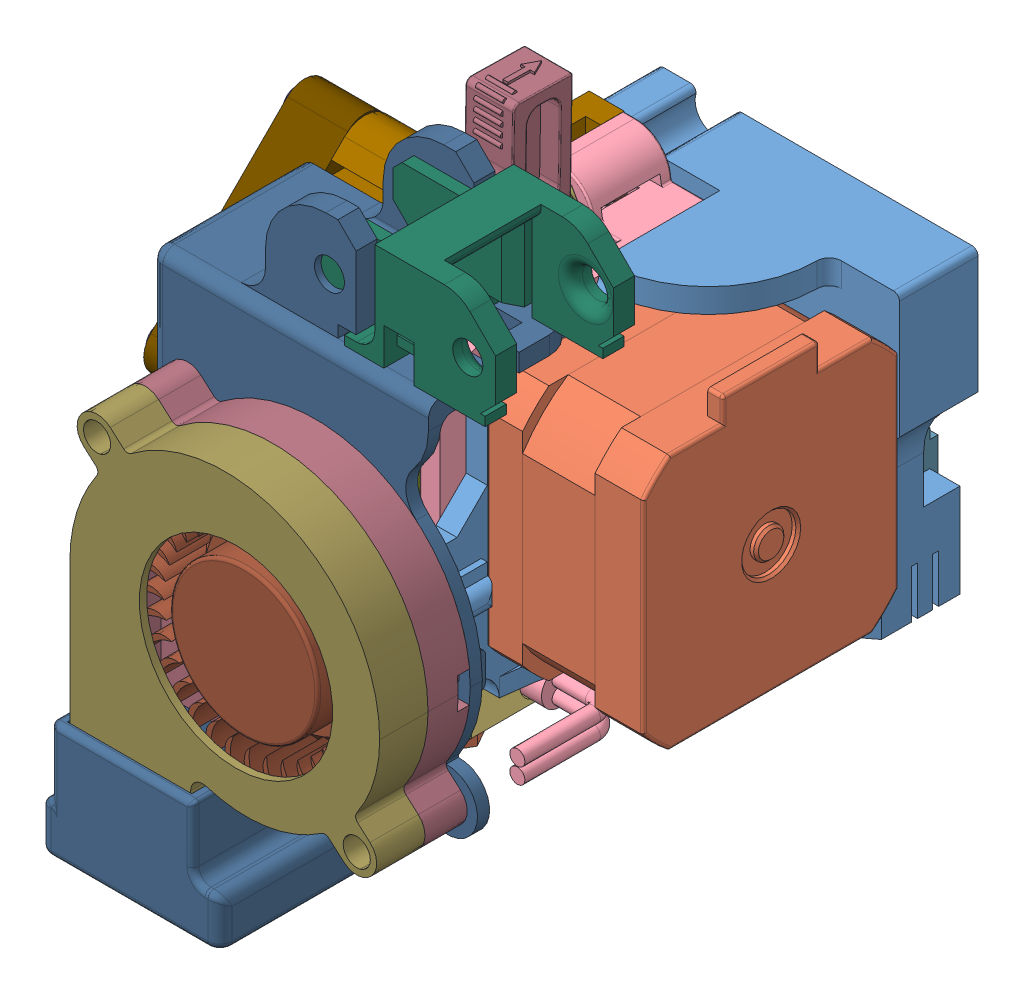
SolidWorks assembly Ensamblaje Titan Aero, configuration Predeterminado. Lengths in mm.
Overall size (76.87 98.82 99.88).
44 component instances, 33 part files, 26 mates.
Components (placement in the parent):
- X-CarriageV2 Titan-1: X-CarriageV2 Titan [Predeterminado] at origin size (55.25 51 75.5)
- Nema 17-1: Nema 17 [NEMA 17 L26] at (26.75 25.5 21) x (0 0 -1) z (1 0 0) size (42.3 46.3 50)
- LJ12A3-4-Z-1: LJ12A3-4-Z [По умолчанию] at (7.55 -17.2 54.5) x (-0.683398 0 0.730046) z (0 -1 0) size (12.21 12.27 81)
- e3d titan areo 1.751-1: e3d titan areo 1.751 [Predeterminado] at (23.25 25.5 21) x (0 0 -1) z (0 1 0) size (64.29 54.44 90.47)
  - Base-1: Base [Predeterminado] at origin size (46 23.41 49.98)
  - 9x5x3mm bearing-1: 9x5x3mm bearing [Predeterminado] at (-15.5 4 15.5) x (1 0 0) z (0 -1 0) size (9 9 3)
  - hobbed wheel-1: hobbed wheel [Predeterminado] at (-15.5 1.6 15.5) x (-0.447437 0 0.894315) z (0 1 0) size (8.6 8.58 20.6)
  - filament gear-1: filament gear [Predeterminado] at (-15.5 8.55 15.5) x (-0.894315 0 -0.447437) z (0 -1 0) size (34 34 4)
  - motor gear-1: motor gear [Predeterminado] at (0 8.5 0) x (-0.681998 0 -0.731354) z (0 -1 0) size (11.99 11.99 9)
  - cover-1: cover [Predeterminado] at (0 24.9 0) x (1 0 0) z (0 0 -1) size (52.63 28.17 55.14)
  - 9x5x3mm bearing-2: 9x5x3mm bearing [Predeterminado] at (-15.5 22.8 15.5) x (1 0 0) z (0 -1 0) size (9 9 3)
  - m3x8-1: m3x8 [Predeterminado] at (20.7 13.6 23.3) x (0 0 1) z (0 1 0) size (5.69 9.65 5.69)
  - M3 nut-1: M3 nut [Predeterminado] at (16.7 13.6 23.3) x (0 1 0) z (0 0 1) size (6.19 2.71 6.57)
  - idler spring-1: idler spring [Predeterminado] at (14.287 13.6 23.3) x (0 0 1) z (-1 0 0) size (6.43 6.45 12.02)
  - tensioner-1: tensioner [Predeterminado] at (0 13.6 0) x (0 -1 0) z (0.017452 0 0.999848) size (8.2 21.54 50.88)
  - idler bearing pin-1: idler bearing pin [Predeterminado] at (-5.2287 9.6 15.5936) x (0.999848 0 -0.017452) z (0 1 0) size (3.04 3.15 9)
  - idler bearing-1: idler bearing [Predeterminado] at (-5.2287 13.6 15.5936) x (0.999848 0 -0.017452) z (0 1 0) size (10 10 4)
  - guide tube-1: guide tube [Predeterminado] at (-10.9 13.6 -7.9) x (-1 0 0) z (0 0 1) size (10.9 16.1 22.25)
  - ISO 7380 - M3 x 28 v1-1: ISO 7380 - M3 x 28 v1 [Predeterminado] at (-15.5 25.94 15.5) x (0 -1 0) z (0 0 1) size (14.65 5.7 5.7)
  - ISO 7380 - M3 x 28 v1-2: ISO 7380 - M3 x 28 v1 [Predeterminado] at (15.5 25.94 15.5) x (0 -1 0) z (0 0 1) size (14.65 5.7 5.7)
  - ISO 7380 - M3 x 28 v1-3: ISO 7380 - M3 x 28 v1 [Predeterminado] at (15.5 25.94 -15.5) x (0 -1 0) z (0 0 1) size (14.65 5.7 5.7)
  - ISO 7380 - M3 x 28 v1-4: ISO 7380 - M3 x 28 v1 [Predeterminado] at (-21.7 25.94 -14.7) x (0 -1 0) z (0 0 -1) size (14.65 5.7 5.7)
  - Fan 40 X 40 X 10 v4-1: Fan 40 X 40 X 10 v4 [Predeterminado] at (-2.3 40.465 3.8274) x (0.707107 0 0.707107) z (-0.707107 0 0.707107) size (40 10.59 40)
  - E3D v6 HotEnd - Heatbreak-1: E3D v6 HotEnd - Heatbreak [Predeterminado] at (-10.9 13.6 -31.7812) x (0 1 0) z (0 0 -1) size (7 7 21.9)
  - E3D v6 HotEnd - Nozzle-1: E3D v6 HotEnd - Nozzle [Predeterminado] at (-10.4145 12.7757 -42.8188) x (0 1 0) z (0 0 -1) size (8.08 7 12.5)
  - E3D v6 HotEnd - Heat Block-1: E3D v6 HotEnd - Heat Block [Predeterminado] at (4.7289 21.3165 -38.3127) x (-1 0 0) z (0 1 0) size (20 11.5 16)
  - Ceramic Cartridge Heater-1: Ceramic Cartridge Heater [Predeterminado] at (-3.5983 1.9238 -34.2531) x (0 0 1) z (0 -1 0) size (6 18 29.25)
  - Thermistor-1: Thermistor [Predeterminado] at (-7 16.1 -36.0312) x (0 -0.5 0.866025) z (-1 0 0) size (1.5 1.5 7.6)
  - HEXAGON SOCKET HEAD CAP SCREWS_SCB3-4-1: HEXAGON SOCKET HEAD CAP SCREWS_SCB3-4 [Predeterminado] at (-2.4 14.6 -33.2312) x (0 1 0) z (1 0 0) size (5.5 5.5 7)
  - HEXAGON SOCKET HEAD CAP SCREWS_SCB3-10-1: HEXAGON SOCKET HEAD CAP SCREWS_SCB3-10 [Predeterminado] at (1.5308 13.8272 -37.4189) x (0 1 0) z (0 0 -1) size (5.5 5.5 13)
  - Flat Washers_PWF3-1: Flat Washers_PWF3 [Predeterminado] at (-2.4 14.6 -33.2312) x (0 1 0) z (1 0 0) size (6 6 0.5)
  - ISO 7380 - M3 x 28 v1-5: ISO 7380 - M3 x 28 v1 [Predeterminado] at (-2.3 45.465 26.4548) x (0 -1 0) z (0.707107 0 0.707107) size (14.65 5.7 5.7)
  - ISO 7380 - M3 x 28 v1-6: ISO 7380 - M3 x 28 v1 [Predeterminado] at (-24.9274 45.465 3.8274) x (0 -1 0) z (0.707107 0 0.707107) size (14.65 5.7 5.7)
  - ISO 7380 - M3 x 28 v1-7: ISO 7380 - M3 x 28 v1 [Predeterminado] at (-2.3 45.465 -18.8) x (0 -1 0) z (0.707107 0 0.707107) size (14.65 5.7 5.7)
  - ISO 7380 - M3 x 28 v1-8: ISO 7380 - M3 x 28 v1 [Predeterminado] at (20.3274 45.465 3.8274) x (0 -1 0) z (0.707107 0 0.707107) size (14.65 5.7 5.7)
- Гайка М12-1: Гайка М12 [По умолчанию] at (7.55 19.5 54.5) x (0.866025 0 0.5) z (0 -1 0) size (16.5 19.05 4.39)
- Гайка М12-2: Гайка М12 [По умолчанию] at (7.55 11.5 54.5) x (0.866025 0 0.5) z (0 -1 0) size (16.5 19.05 4.39)
- LayerFanSupport-Titan-1: LayerFanSupport-Titan [Predeterminado] at (-3.56 4.8 51.3) x (0 0 -1) z (0 -1 0) size (49.98 56.12 97.13)
- Radial-Cooling-Fan-5015-DC12V-1: Radial-Cooling-Fan-5015-DC12V [По умолчанию] at (24.44 25.4 66.3) x (1 0 0) z (0 -1 0) size (51.3 15 51.07)
  - turbine-1: turbine [По умолчанию] at (0 3.2 0) x (0.990476 0 -0.137682) z (0.137682 0 0.990476) size (38.96 10.5 38.91)
  - top-3: top [По умолчанию] at (0 15 0) size (51.3 8 51.07)
  - bottom-1: bottom [По умолчанию] at origin size (51.3 8.5 51.07)
- MGN12C-1: MGN12C [Predeterminado] at (42.3453 36.5334 -17) x (-0.999999 -0.001343 0) z (-0.001343 0.999999 0) size (34.7 10 27)
- Eslabon 15-2: Eslabon 15 [Predeterminado] at (50.915 79.5 45.7925) x (-1 0 0) z (0 0 1) size (34 17 23)
Mates (geometry in assembly coordinates):
- Concéntrica1: concentric aligned: cylinder of X-CarriageV2 Titan-1 through (58.1455 41 36.5) axis (-1 0 0) radius 1.55; cylinder of Nema 17-1 through (26.75 41 36.5) axis (-1 0 0) radius 1.25
- Concéntrica2: concentric aligned: cylinder of X-CarriageV2 Titan-1 through (58.1455 41 5.5) axis (-1 0 0) radius 1.55; circle of Nema 17-1
- Coincidente1: coincident anti-aligned: plane of X-CarriageV2 Titan-1 through (26.75 47 42) normal (1 0 0); plane of Nema 17-1 through (26.75 25.5 21) normal (-1 0 0)
- Concéntrica3: concentric anti-aligned: cylinder of X-CarriageV2 Titan-1 through (7.55 -1.8241 54.5) axis (0 1 0) radius 6.125; cylinder of LJ12A3-4-Z-1 through (7.55 -17.2 54.5) axis (0 -1 0) radius 5.25
- Concéntrica4: concentric anti-aligned: cylinder of X-CarriageV2 Titan-1 through (58.1455 41 5.5) axis (-1 0 0) radius 1.55; cylinder of e3d titan areo 1.751-1/Base-1 through (19.75 41 5.5) axis (1 0 0) radius 1.825
- Concéntrica5: concentric anti-aligned: cylinder of X-CarriageV2 Titan-1 through (58.1455 41 36.5) axis (-1 0 0) radius 1.55; cylinder of e3d titan areo 1.751-1/hobbed wheel-1 through (11.35 41 36.5) axis (1 0 0) radius 1.65
- Coincidente2: coincident anti-aligned: plane of X-CarriageV2 Titan-1 through (23.25 47 42) normal (-1 0 0); plane of e3d titan areo 1.751-1/Base-1 through (23.25 26.8 23.3) normal (1 0 0)
- Concéntrica6: concentric aligned: circle of Гайка М12-1; circle of X-CarriageV2 Titan-1
- Coincidente5: coincident anti-aligned: plane of X-CarriageV2 Titan-1 through (0 19.5 0) normal (0 1 0); plane of Гайка М12-1 through (4.9 19.5 59.0899) normal (0 -1 0)
- Paralelo1: parallel aligned: plane of X-CarriageV2 Titan-1 through (-2.25 19.5 62.5) normal (0 0 1); plane of Гайка М12-1 through (12.3131 23.5 62.75) normal (0 0 1)
- Concéntrica7: concentric aligned: cylinder of LJ12A3-4-Z-1 through (7.55 -17.2 54.5) axis (0 -1 0) radius 5.25; circle of Гайка М12-2
- Coincidente7: coincident anti-aligned: plane of X-CarriageV2 Titan-1 through (23.25 15.5 60) normal (0 -1 0); plane of Гайка М12-2 through (4.9 15.5 59.0899) normal (0 1 0)
- Paralelo2: parallel aligned: plane of X-CarriageV2 Titan-1 through (-2.25 19.5 62.5) normal (0 0 1); plane of Гайка М12-2 through (12.3131 15.5 62.75) normal (0 0 1)
- Concéntrica8: concentric anti-aligned: circle of e3d titan areo 1.751-1/ISO 7380 - M3 x 28 v1-1; cylinder of LayerFanSupport-Titan-1 through (-1.56 41 36.5) axis (-1 0 0) radius 1.55
- Concéntrica9: concentric anti-aligned: circle of e3d titan areo 1.751-1/ISO 7380 - M3 x 28 v1-4; cylinder of LayerFanSupport-Titan-1 through (-1.56 10.8 42.7) axis (-1 0 0) radius 1.55
- Coincidente9: coincident anti-aligned: plane of e3d titan areo 1.751-1/cover-1 through (-2.69 26.8 23.3) normal (-1 0 0); plane of LayerFanSupport-Titan-1 through (-2.69 10.8 42.7) normal (1 0 0)
- Coincidente10: coincident aligned: plane of LJ12A3-4-Z-1 through (7.55 -17.2 54.5) normal (0 -1 0); plane of LayerFanSupport-Titan-1 through (-3.56 -17.2 51.3) normal (0 -1 0)
- Concéntrica10: concentric aligned: cylinder of LayerFanSupport-Titan-1 through (44.44 7.4 59.9159) axis (0 0 1) radius 1.55; cylinder of Radial-Cooling-Fan-5015-DC12V-1/top-3 through (44.44 7.4 73.3) axis (0 0 1) radius 2.25
- Concéntrica11: concentric aligned: cylinder of LayerFanSupport-Titan-1 through (1.44 45.4 59.9159) axis (0 0 1) radius 1.55; cylinder of Radial-Cooling-Fan-5015-DC12V-1/top-3 through (1.44 45.4 73.3) axis (0 0 1) radius 2.25
- Coincidente11: coincident anti-aligned: plane of LayerFanSupport-Titan-1 through (-1.56 4.8 66.3) normal (0 0 1); plane of Radial-Cooling-Fan-5015-DC12V-1/bottom-1 through (1.44 45.4 66.3) normal (0 0 -1)
- Concéntrica12: concentric aligned: cylinder of X-CarriageV2 Titan-1 through (17.5 33 -17.3841) axis (0 0 1) radius 1.55; cylinder of MGN12C-1 through (17.5 33 -12) axis (0 0 1) radius 1.5
- Concéntrica13: concentric aligned: cylinder of X-CarriageV2 Titan-1 through (32.5 33 -17.3841) axis (0 0 1) radius 1.55; cylinder of MGN12C-1 through (32.5 33 -12) axis (0 0 1) radius 1.5
- Coincidente12: coincident anti-aligned: plane of X-CarriageV2 Titan-1 through (0 0 -7) normal (0 0 -1); plane of MGN12C-1 through (42.3453 36.5334 -7) normal (0 0 1)
- Concéntrica14: concentric aligned: cylinder of LayerFanSupport-Titan-1 through (22.915 71 34.2214) axis (0 0 1) radius 2.5; circle of Eslabon 15-2
- Coincidente14: coincident anti-aligned: plane of LayerFanSupport-Titan-1 through (27.315 79.5 60.7925) normal (0 0 -1); plane of Eslabon 15-2 through (30.915 77.5 60.7925) normal (0 0 1)
- Coincidente15: coincident anti-aligned: plane of LayerFanSupport-Titan-1 through (-1.19 62.5 62.8) normal (0 1 0); plane of Eslabon 15-2 through (50.915 62.5 45.7925) normal (0 -1 0)
